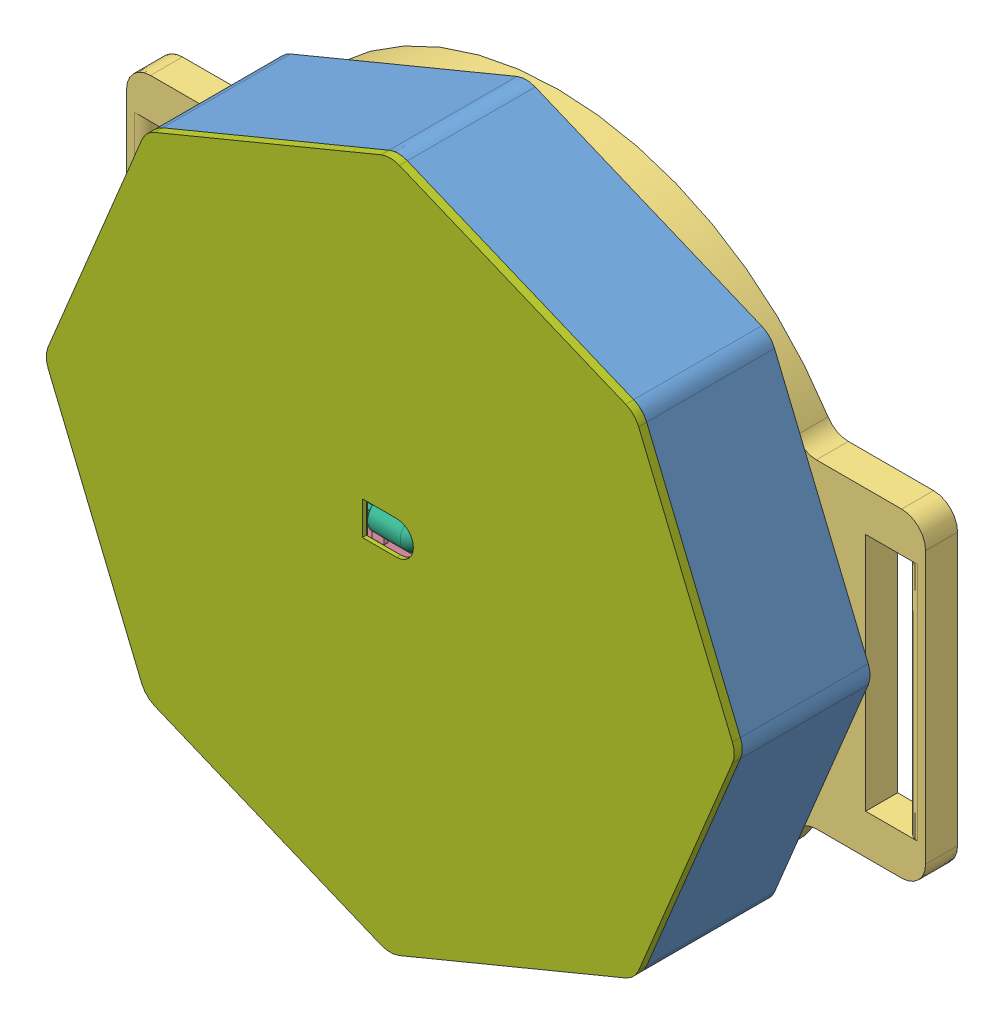
SolidWorks assembly Assemblage, configuration Défaut. Lengths in mm.
Overall size (100 86.1 21).
22 component instances, 8 part files, 35 mates.
Components (placement in the parent):
- Base-1: Base [Défaut] at (3.5859 0.8827 86.5914) size (86.1 86.1 16)
- Magnet-1: Magnet [Défaut] at (33.5859 0.8827 83.8914) size (6 6 2.6)
- Magnet-2: Magnet [Défaut] at (3.5859 30.8827 83.8914) size (6 6 2.6)
- Magnet-3: Magnet [Défaut] at (-26.4141 0.8827 83.8914) size (6 6 2.6)
- Magnet-4: Magnet [Défaut] at (3.5859 -29.1173 83.8914) size (6 6 2.6)
- Strap_support-1: Strap_support [Défaut] at (3.5859 0.8827 82.5914) size (100 80 4)
- Magnet-5: Magnet [Défaut] at (3.5859 -29.1173 86.9914) size (6 6 2.6)
- Magnet-6: Magnet [Défaut] at (-26.4141 0.8827 86.9914) size (6 6 2.6)
- Magnet-7: Magnet [Défaut] at (3.5859 30.8827 86.6914) size (6 6 2.6)
- Magnet-8: Magnet [Défaut] at (33.5859 0.8827 86.9914) x (0.986935 0.161119 0) z (0 0 1) size (6 6 2.6)
- WEMOS D1 mini-1: WEMOS D1 mini [Default] at (16.6859 15.2827 98.3914) x (1 0 0) z (0 1 0) size (25.6 7 34.4)
- LED-1: LED [Défaut] at (-3.9141 27.7327 90.5914) size (15 9.5 1.9)
- LED-2: LED [Défaut] at (17.2541 25.1514 90.5914) x (0.707107 -0.707107 0) z (0 0 1) size (15 9.5 1.9)
- LED-3: LED [Défaut] at (30.3971 8.3579 90.5914) x (0 -1 0) z (0 0 1) size (15 9.5 1.9)
- LED-4: LED [Défaut] at (27.8158 -12.8104 90.5914) x (-0.707107 -0.707107 0) z (0 0 1) size (15 9.5 1.9)
- LED-5: LED [Défaut] at (11.0223 -25.9533 90.5914) x (-1 0 0) z (0 0 1) size (15 9.5 1.9)
- LED-6: LED [Défaut] at (-10.146 -23.372 90.5914) x (-0.707107 0.707107 0) z (0 0 1) size (15 9.5 1.9)
- LED-7: LED [Défaut] at (-23.2889 -6.5786 90.5914) x (0 1 0) z (0 0 1) size (15 9.5 1.9)
- LED-8: LED [Défaut] at (-20.7076 14.5897 90.5914) x (0.707107 0.707107 0) z (0 0 1) size (15 9.5 1.9)
- IR_receiver-1: IR_receiver [Défaut] at (0.7373 0.4576 99.3914) size (12.8 5.4 4.2)
- Front-1: Front [Défaut] at (21.7637 -8.4575 102.5914) size (86.1 86.1 6)
- Battery-1: Battery [Défaut] at (21.1214 19.6047 93.5914) x (0 -1 0) z (0 0 -1) size (38 37 6)
Mates (geometry in assembly coordinates):
- Coïncidente1: coincident anti-aligned: plane of Magnet-2 through (3.5859 30.8827 83.8914) normal (0 0 -1); plane of Strap_support-1 through (3.5859 30.8827 83.8914) normal (0 0 1)
- Coaxiale1: concentric aligned: cylinder of Magnet-2 through (3.5859 30.8827 86.4914) axis (0 0 -1) radius 3; cylinder of Strap_support-1 through (3.5859 30.8827 86.5914) axis (0 0 -1) radius 3.1
- Coïncidente2: coincident anti-aligned: plane of Magnet-3 through (-26.4141 0.8827 83.8914) normal (0 0 -1); plane of Strap_support-1 through (-26.4141 0.8827 83.8914) normal (0 0 1)
- Coaxiale2: concentric aligned: cylinder of Magnet-3 through (-26.4141 0.8827 86.4914) axis (0 0 -1) radius 3; cylinder of Strap_support-1 through (-26.4141 0.8827 86.5914) axis (0 0 -1) radius 3.1
- Coïncidente3: coincident anti-aligned: plane of Magnet-4 through (3.5859 -29.1173 83.8914) normal (0 0 -1); plane of Strap_support-1 through (3.5859 -29.1173 83.8914) normal (0 0 1)
- Coaxiale3: concentric aligned: cylinder of Magnet-4 through (3.5859 -29.1173 86.4914) axis (0 0 -1) radius 3; cylinder of Strap_support-1 through (3.5859 -29.1173 86.5914) axis (0 0 -1) radius 3.1
- Coïncidente4: coincident anti-aligned: plane of Magnet-1 through (33.5859 0.8827 83.8914) normal (0 0 -1); plane of Strap_support-1 through (33.5859 0.8827 83.8914) normal (0 0 1)
- Coaxiale4: concentric aligned: cylinder of Magnet-1 through (33.5859 0.8827 86.4914) axis (0 0 -1) radius 3; cylinder of Strap_support-1 through (33.5859 0.8827 86.5914) axis (0 0 -1) radius 3.1
- Coïncidente5: coincident anti-aligned: plane of Base-1 through (3.5859 0.8827 86.5914) normal (0 0 -1); plane of Strap_support-1 through (3.5859 0.8827 86.5914) normal (0 0 1)
- Coaxiale5: concentric aligned: cylinder of Base-1 through (33.5859 0.8827 89.5914) axis (0 0 -1) radius 3.1; cylinder of Magnet-8 through (33.5859 0.8827 89.5914) axis (0 0 -1) radius 3
- Coïncidente6: coincident anti-aligned: plane of Base-1 through (33.5859 0.8827 89.5914) normal (0 0 -1); plane of Magnet-8 through (33.5859 0.8827 89.5914) normal (0 0 1)
- Coïncidente7: coincident anti-aligned: plane of Base-1 through (3.5859 -29.1173 89.5914) normal (0 0 -1); plane of Magnet-5 through (3.5859 -29.1173 89.5914) normal (0 0 1)
- Coaxiale6: concentric aligned: cylinder of Base-1 through (3.5859 -29.1173 89.5914) axis (0 0 -1) radius 3.1; cylinder of Magnet-5 through (3.5859 -29.1173 89.5914) axis (0 0 -1) radius 3
- Coïncidente8: coincident anti-aligned: plane of Base-1 through (-26.4141 0.8827 89.5914) normal (0 0 -1); plane of Magnet-6 through (-26.4141 0.8827 89.5914) normal (0 0 1)
- Coaxiale7: concentric aligned: cylinder of Base-1 through (-26.4141 0.8827 89.5914) axis (0 0 -1) radius 3.1; cylinder of Magnet-6 through (-26.4141 0.8827 89.5914) axis (0 0 -1) radius 3
- Coaxiale8: concentric aligned: cylinder of Base-1 through (3.5859 30.8827 89.5914) axis (0 0 -1) radius 3.1; cylinder of Magnet-7 through (3.5859 30.8827 89.2914) axis (0 0 -1) radius 3
- Coaxiale9: concentric aligned: cylinder of Base-1 through (3.5859 30.8827 89.5914) axis (0 0 -1) radius 3.1; cylinder of Strap_support-1 through (3.5859 30.8827 86.5914) axis (0 0 -1) radius 3.1
- Coaxiale10: concentric aligned: cylinder of Base-1 through (3.5859 -29.1173 89.5914) axis (0 0 -1) radius 3.1; cylinder of Strap_support-1 through (3.5859 -29.1173 86.5914) axis (0 0 -1) radius 3.1
- Distance1: distance = 0 mm aligned: plane of WEMOS D1 mini-1 through (14.1859 -19.1173 96.8914) normal (0 -1 0); plane of Strap_support-1 through (-31.0552 -19.1173 86.5914) normal (0 -1 0)
- Coïncidente15: coincident anti-aligned: plane of Base-1 through (3.5859 30.8827 90.5914) normal (0 0 1); plane of LED-1 through (-3.9141 27.7327 90.5914) normal (0 0 -1)
- Tangent2: tangent aligned: cylinder of Base-1 through (3.5859 30.8827 89.5914) axis (0 0 -1) radius 4.1; plane of LED-1 through (1.0859 34.9827 92.4914) normal (0 1 0)
- Parallèle2: parallel aligned: plane of Strap_support-1 through (-31.0552 -19.1173 86.5914) normal (0 -1 0); plane of LED-1 through (-3.9141 27.7327 90.8914) normal (0 -1 0)
- Distance8: distance = 0 mm: line of LED-1 through (3.5859 34.9827 90.8914) axis (0 0 1); line of Base-1 through (3.5859 43.096 87.5914) axis (0 -1 0)
- Coaxiale11: concentric aligned: cylinder of Base-1 through (3.5859 40.9312 96.5914) axis (0 0 -1) radius 3; cylinder of Front-1 through (3.5859 40.9312 103.5914) axis (0 0 -1) radius 3
- Coaxiale12: concentric aligned: cylinder of Base-1 through (43.6344 0.8827 96.5914) axis (0 0 -1) radius 3; cylinder of Front-1 through (43.6344 0.8827 103.5914) axis (0 0 -1) radius 3
- Coïncidente22: coincident anti-aligned: plane of Base-1 through (3.5859 0.8827 87.5914) normal (0 0 1); plane of Battery-1 through (21.1214 19.6047 87.5914) normal (0 0 -1)
- Parallèle3: parallel aligned: plane of Strap_support-1 through (53.5859 -19.1173 86.5914) normal (1 0 0); plane of Battery-1 through (21.1214 19.6047 87.5914) normal (1 0 0)
- Coïncidente25: coincident anti-aligned: plane of Base-1 through (21.1214 -6.6173 92.5914) normal (-1 0 0); plane of Battery-1 through (21.1214 19.6047 87.5914) normal (1 0 0)
- Coïncidente26: coincident anti-aligned: plane of Base-1 through (-0.8786 19.6047 92.5914) normal (0 -1 0); plane of Battery-1 through (21.1214 19.6047 87.5914) normal (0 1 0)
- Coïncidente27: coincident anti-aligned: plane of WEMOS D1 mini-1 through (16.6859 15.2827 93.5914) normal (0 0 -1); plane of Battery-1 through (21.1214 19.6047 93.5914) normal (0 0 1)
- Distance9: distance = 30 mm aligned: plane of WEMOS D1 mini-1 through (-8.9141 -16.6173 96.8914) normal (-1 0 0); plane of Strap_support-1 through (-38.9141 -14.1173 73.8914) normal (-1 0 0)
- Coïncidente29: coincident anti-aligned: plane of WEMOS D1 mini-1 through (16.6859 15.2827 99.3914) normal (0 0 1); plane of IR_receiver-1 through (0.7373 0.4576 99.3914) normal (0 0 -1)
- Distance10: distance = 0.5 mm aligned: plane of IR_receiver-1 through (7.5373 0.4576 101.6914) normal (1 0 0); plane of WEMOS D1 mini-1 through (8.0373 15.2827 99.3914) normal (1 0 0)
- Distance11: distance = 0.4 mm aligned: plane of WEMOS D1 mini-1 through (16.6859 5.4576 99.3914) normal (0 1 0); plane of IR_receiver-1 through (0.7373 5.8576 101.6914) normal (0 1 0)
- Coïncidente33: coincident anti-aligned: plane of Base-1 through (3.5859 40.9312 102.5914) normal (0 0 1); plane of Front-1 through (3.5859 40.9312 102.5914) normal (0 0 -1)
